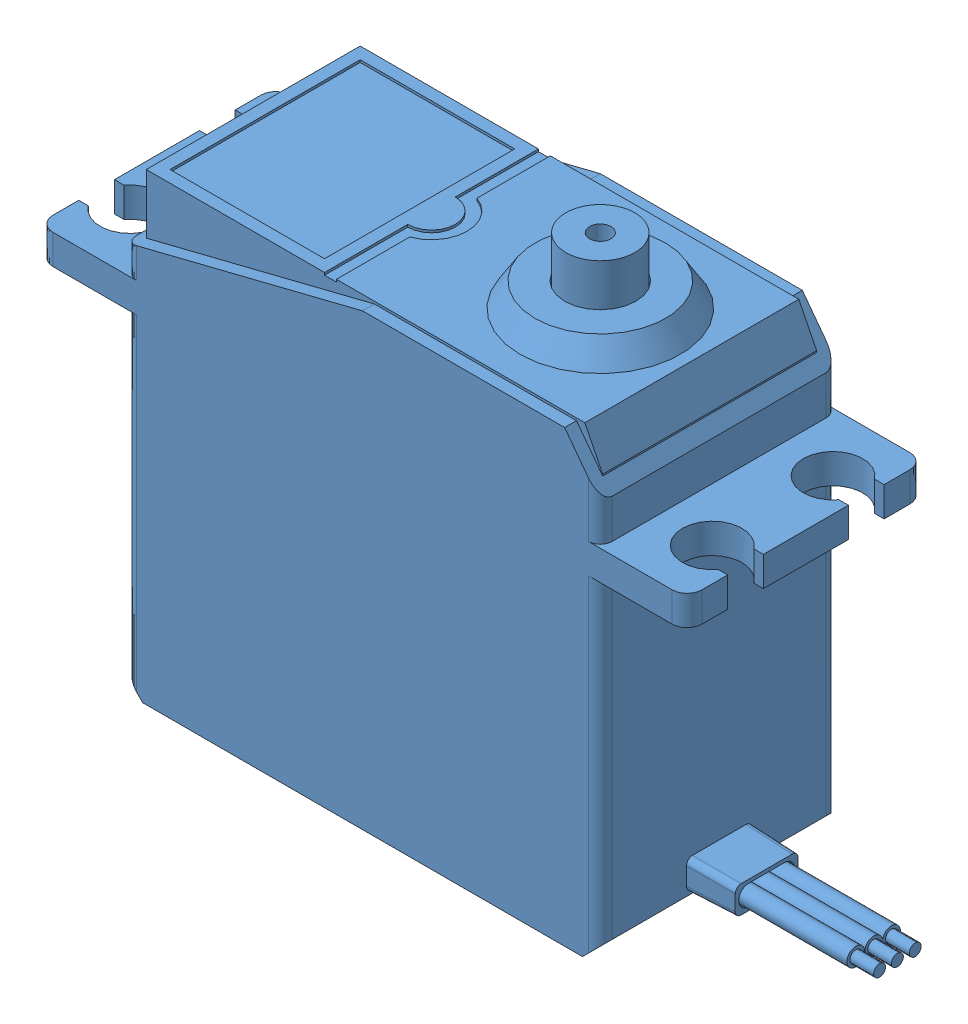
SolidWorks assembly JOINT2, configuration Default. Lengths in mm.
Overall size (64.77 48.5 30).
3 component instances, 2 part files, 2 mates.
Components (placement in the parent):
- Servo motor-1: Servo motor [sin servohorn] at (9.1899 16.3067 49.4436) size (62.3 43.5 20)
- SUPPSER1 X8-2: SUPPSER1 X8 [Default] at (9.1899 24.3067 44.4436) x (0 0 -1) z (0 -1 0) size (15 59.54 33)
- SUPPSER1 X8-3: SUPPSER1 X8 [Default] at (9.1899 24.3067 54.4436) x (0 0 1) z (0 -1 0) size (15 59.54 33)
Mates (geometry in assembly coordinates):
- Width1: width anti-aligned: plane of Servo motor-1 through (-10.8101 44.3067 39.4436) normal (-1 0 0); plane of SUPPSER1 X8-2 through (29.1899 44.3067 39.4436) normal (1 0 0); plane of Servo motor-1 through (34.1899 16.3067 49.4436) normal (1 0 0); plane of SUPPSER1 X8-2 through (-15.8101 16.3067 49.4436) normal (-1 0 0)
- Coincident7: coincident aligned: plane of Servo motor-1 through (29.1899 16.3067 39.4436) normal (0 -1 0); plane of SUPPSER1 X8-3 through (9.1899 16.3067 54.4436) normal (0 -1 0)
